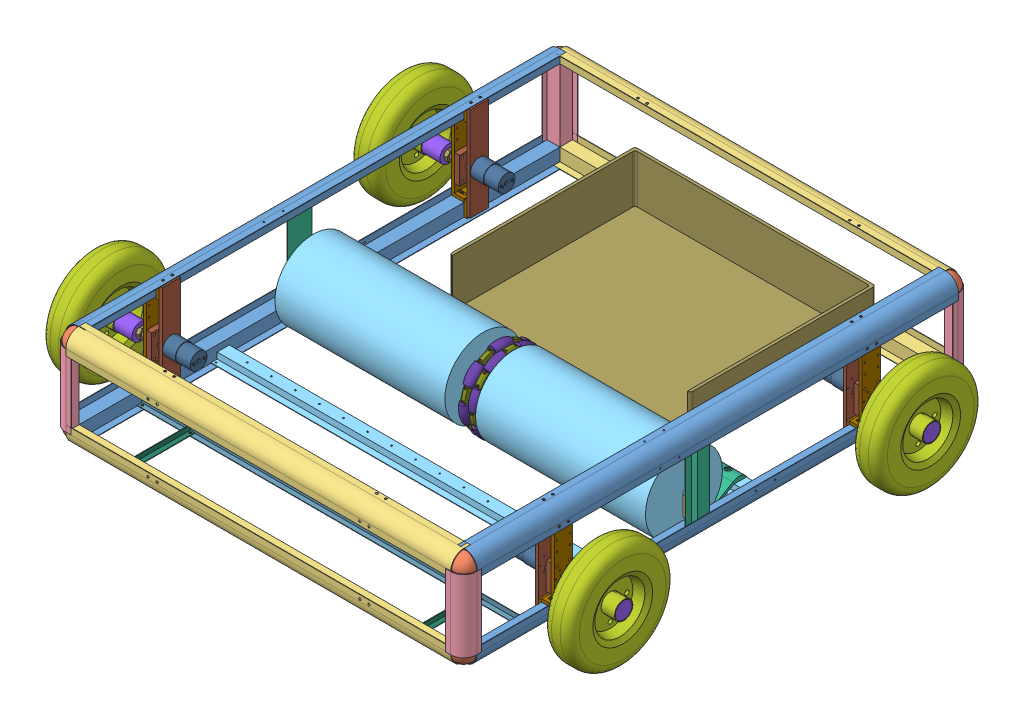
SolidWorks assembly Chasis Completo, configuration Predeterminado. Lengths in mm.
Overall size (1103.46 320.76 1054.8).
153 component instances, 30 part files, 76 mates.
Components (placement in the parent):
- Chasis Con Pala-1: Chasis Con Pala [Predeterminado] at (1005.1778 -86.1734 2178.1908) x (0 0 1) z (-1 0 0) size (1054.8 242.15 854.8)
  - ChasisConBasesMotor-1: ChasisConBasesMotor [Predeterminado] at (-1083.3487 23.6381 -1054.8) size (1054.8 204.8 854.8)
    - Chasis-1: Chasis [Predeterminado] at (1241.3285 35.949 1054.8) size (1054.8 204.8 854.8)
      - MarcoBaseParales-1: MarcoBaseParales [Predeterminado] at (-1311.4332 104.5123 1) size (1054.8 177.4 854.8)
        - MarcoBase-1: MarcoBase [Predeterminado] at (-969.9374 -232.4227 646.0297) x (0 1 0) z (1 0 0) size (77.4 854.8 1053.8)
          - Angulo-1: Angulo [Predeterminado] at (-20.7639 -5.9297 1000) x (-1 0 0) z (0 0 1) size (40.4 40.4 1000)
          - Angulo 90 perfil-1: Angulo 90 perfil [Predeterminado] at (-7.0639 7.7703 1500) x (-1 0 0) z (0 0 -1) size (75.4 75.4 75.4)
          - Angulo 90 perfil-2: Angulo 90 perfil [Predeterminado] at (-7.0639 7.7703 500) x (0 0 -1) z (1 0 0) size (75.4 75.4 75.4)
          - AnguloFrontal-1: AnguloFrontal [Predeterminado] at (-20.7639 407.7703 486.3) x (-1 0 0) z (0 -1 0) size (40.4 40.4 800)
          - AnguloFrontal-2: AnguloFrontal [Predeterminado] at (-20.7639 407.7703 1512.7) x (-1 0 0) z (0 1 0) size (40.4 40.4 800)
          - Angulo-2: Angulo [Predeterminado] at (-20.7639 821.4703 999) x (0 1 0) z (0 0 1) size (40.4 40.4 1000)
          - Angulo 90 perfil-3: Angulo 90 perfil [Predeterminado] at (-7.0639 807.7703 1499) x (0 1 0) z (0 0 -1) size (75.4 75.4 75.4)
          - Angulo 90 perfil-5: Angulo 90 perfil [Predeterminado] at (-7.0639 807.7703 500) x (0 0 -1) z (0 -1 0) size (75.4 75.4 75.4)
        - AnguloParal-1: AnguloParal [Predeterminado] at (-483.6374 -164.4866 1467.5) x (-1 0 0) z (0 1 0) size (37.4 37.4 150)
        - AnguloParal-2: AnguloParal [Predeterminado] at (542.7626 -164.4866 1467.5) x (1 0 0) z (0 -1 0) size (37.4 37.4 150)
        - AnguloParal-3: AnguloParal [Predeterminado] at (543.7626 -164.4866 640.1) x (1 0 0) z (0 1 0) size (37.4 37.4 150)
        - AnguloParal-4: AnguloParal [Predeterminado] at (-483.6374 -164.4866 640.2072) x (-1 0 0) z (0 -1 0) size (37.4 37.4 150)
      - MarcoBase-1: MarcoBase [Predeterminado] at (-282.3706 7.9618 647.0297) x (0 -1 0) z (-1 0 0) size (77.4 854.8 1053.8)
        - Angulo-1: Angulo [Predeterminado] at (-20.7639 -5.9297 1000) x (-1 0 0) z (0 0 1) size (40.4 40.4 1000)
        - Angulo 90 perfil-1: Angulo 90 perfil [Predeterminado] at (-7.0639 7.7703 1500) x (-1 0 0) z (0 0 -1) size (75.4 75.4 75.4)
        - Angulo 90 perfil-2: Angulo 90 perfil [Predeterminado] at (-7.0639 7.7703 500) x (0 0 -1) z (1 0 0) size (75.4 75.4 75.4)
        - AnguloFrontal-1: AnguloFrontal [Predeterminado] at (-20.7639 407.7703 486.3) x (-1 0 0) z (0 -1 0) size (40.4 40.4 800)
        - AnguloFrontal-2: AnguloFrontal [Predeterminado] at (-20.7639 407.7703 1512.7) x (-1 0 0) z (0 1 0) size (40.4 40.4 800)
        - Angulo-2: Angulo [Predeterminado] at (-20.7639 821.4703 999) x (0 1 0) z (0 0 1) size (40.4 40.4 1000)
        - Angulo 90 perfil-3: Angulo 90 perfil [Predeterminado] at (-7.0639 807.7703 1499) x (0 1 0) z (0 0 -1) size (75.4 75.4 75.4)
        - Angulo 90 perfil-5: Angulo 90 perfil [Predeterminado] at (-7.0639 807.7703 500) x (0 0 -1) z (0 -1 0) size (75.4 75.4 75.4)
    - Perfil Cuadrado-1: Perfil Cuadrado [Predeterminado] at (-140.5421 -125.4063 2109.5744) x (0.999999 0 0.001266) z (-0.001266 0 0.999999) size (50.8 13.7 800)
  - Pala Final con cinta-1: Pala Final con cinta [Predeterminado] at (-1316.8259 -114.6069 1804.6573) x (-0.999999 0 -0.001266) z (0.001266 0 -0.999999) size (135.72 60.94 750)
    - Pala Final-1: Pala Final [Predeterminado] at (-89.6383 2.5012 300) size (135.72 55.88 750)
      - SoportePala-1: SoportePala [Predeterminado] at (-102.2251 6.5255 0) size (135.72 55.88 150)
        - pala2-1: pala2 [Predeterminado] at (85.8775 17.5121 150) size (98.62 43.88 150)
        - protecto pala-1: protecto pala [Predeterminado] at (39.6775 -17.4879 150) size (110.9 15 150)
      - SoportePala-2: SoportePala [Predeterminado] at (-102.2251 6.5255 150) size (135.72 55.88 150)
        - pala2-1: pala2 [Predeterminado] at (85.8775 17.5121 150) size (98.62 43.88 150)
        - protecto pala-1: protecto pala [Predeterminado] at (39.6775 -17.4879 150) size (110.9 15 150)
      - SoportePala-3: SoportePala [Predeterminado] at (-102.2251 6.5255 300) size (135.72 55.88 150)
        - pala2-1: pala2 [Predeterminado] at (85.8775 17.5121 150) size (98.62 43.88 150)
        - protecto pala-1: protecto pala [Predeterminado] at (39.6775 -17.4879 150) size (110.9 15 150)
      - SoportePala-4: SoportePala [Predeterminado] at (-102.2251 6.5255 450) size (135.72 55.88 150)
        - pala2-1: pala2 [Predeterminado] at (85.8775 17.5121 150) size (98.62 43.88 150)
        - protecto pala-1: protecto pala [Predeterminado] at (39.6775 -17.4879 150) size (110.9 15 150)
      - SoportePala-5: SoportePala [Predeterminado] at (-102.2251 6.5255 600) size (135.72 55.88 150)
        - pala2-1: pala2 [Predeterminado] at (85.8775 17.5121 150) size (98.62 43.88 150)
        - protecto pala-1: protecto pala [Predeterminado] at (39.6775 -17.4879 150) size (110.9 15 150)
    - cinta flexy Recogedor-1: cinta flexy Recogedor [Predeterminado] at (-170.4213 -15.5255 750) x (0 0 1) z (-0.5 0.866025 0) size (750 40 4)
- Soporte Principal Del Chasis-1: Soporte Principal Del Chasis [Predeterminado] at (328.5899 -87.131 1174.7549) x (0 0 -1) z (1 0 0) size (71.11 203.98 109.8)
  - soporte Llantas-1: soporte Llantas [Predeterminado] at (-199.0451 0.5704 44.994) size (71.11 203.98 26.69)
  - instrument ball bearing_ai-1: instrument ball bearing_ai [Rodamiento Rodillo Llanta] at (-199.0451 -22.4296 36.994) x (0 0 -1) z (1 0 0) size (6.35 28.57 28.57)
  - SOPORTE BALINERA-1: SOPORTE BALINERA [Predeterminado] at (-199.0451 -22.4296 33.819) size (38 56 10.5)
  - hex jam nut_ai-1: hex jam nut_ai [HJNUT 0.5000-13-D-S] at (-199.0451 -22.4296 73.5162) x (0.739057 0.673642 0) z (0 0 1) size (19.05 22 8.2)
  - heavy hex finished bolt_ai-1: heavy hex finished bolt_ai [Tornilleria LLantas] at (-199.0451 -22.4296 -3.681) x (0 0 1) z (0.319798 -0.947486 0) size (109.8 25.66 22.23)
- Soporte Principal Del Chasis-2: Soporte Principal Del Chasis [Predeterminado] at (328.5899 -87.131 534.7549) x (0 0 -1) z (1 0 0) size (71.11 203.98 109.8)
  - soporte Llantas-1: soporte Llantas [Predeterminado] at (-199.0451 0.5704 44.994) size (71.11 203.98 26.69)
  - instrument ball bearing_ai-1: instrument ball bearing_ai [Rodamiento Rodillo Llanta] at (-199.0451 -22.4296 36.994) x (0 0 -1) z (1 0 0) size (6.35 28.57 28.57)
  - SOPORTE BALINERA-1: SOPORTE BALINERA [Predeterminado] at (-199.0451 -22.4296 33.819) size (38 56 10.5)
  - hex jam nut_ai-1: hex jam nut_ai [HJNUT 0.5000-13-D-S] at (-199.0451 -22.4296 73.5162) x (0.739057 0.673642 0) z (0 0 1) size (19.05 22 8.2)
  - heavy hex finished bolt_ai-1: heavy hex finished bolt_ai [Tornilleria LLantas] at (-199.0451 -22.4296 -3.681) x (0 0 1) z (0.319798 -0.947486 0) size (109.8 25.66 22.23)
- Soporte Principal Del Chasis-3: Soporte Principal Del Chasis [Predeterminado] at (-427.8342 -87.131 933.8451) x (0 0 1) z (-1 0 0) size (71.11 203.98 109.8)
  - soporte Llantas-1: soporte Llantas [Predeterminado] at (-199.0451 0.5704 44.994) size (71.11 203.98 26.69)
  - instrument ball bearing_ai-1: instrument ball bearing_ai [Rodamiento Rodillo Llanta] at (-199.0451 -22.4296 36.994) x (0 0 -1) z (1 0 0) size (6.35 28.57 28.57)
  - SOPORTE BALINERA-1: SOPORTE BALINERA [Predeterminado] at (-199.0451 -22.4296 33.819) size (38 56 10.5)
  - hex jam nut_ai-1: hex jam nut_ai [HJNUT 0.5000-13-D-S] at (-199.0451 -22.4296 73.5162) x (0.739057 0.673642 0) z (0 0 1) size (19.05 22 8.2)
  - heavy hex finished bolt_ai-1: heavy hex finished bolt_ai [Tornilleria LLantas] at (-199.0451 -22.4296 -3.681) x (0 0 1) z (0.319798 -0.947486 0) size (109.8 25.66 22.23)
- Soporte Principal Del Chasis-4: Soporte Principal Del Chasis [Predeterminado] at (-427.8342 -87.131 1573.8451) x (0 0 1) z (-1 0 0) size (71.11 203.98 109.8)
  - soporte Llantas-1: soporte Llantas [Predeterminado] at (-199.0451 0.5704 44.994) size (71.11 203.98 26.69)
  - instrument ball bearing_ai-1: instrument ball bearing_ai [Rodamiento Rodillo Llanta] at (-199.0451 -22.4296 36.994) x (0 0 -1) z (1 0 0) size (6.35 28.57 28.57)
  - SOPORTE BALINERA-1: SOPORTE BALINERA [Predeterminado] at (-199.0451 -22.4296 33.819) size (38 56 10.5)
  - hex jam nut_ai-1: hex jam nut_ai [HJNUT 0.5000-13-D-S] at (-199.0451 -22.4296 73.5162) x (0.739057 0.673642 0) z (0 0 1) size (19.05 22 8.2)
  - heavy hex finished bolt_ai-1: heavy hex finished bolt_ai [Tornilleria LLantas] at (-199.0451 -22.4296 -3.681) x (0 0 1) z (0.319798 -0.947486 0) size (109.8 25.66 22.23)
- soporte en T-1: soporte en T [Predeterminado] at (-49.6222 -186.9416 1423.3) x (0 0 -1) z (1 0 0) size (20 10.5 800)
- soporte en T pequeño-1: soporte en T pequeño [Predeterminado] at (249.8778 -185.9416 1488.8) size (20 10.5 130)
- soporte en T pequeño-2: soporte en T pequeño [Predeterminado] at (-349.1222 -185.9416 1488.8) size (20 10.5 130)
- Cepillo Completo-2: Cepillo Completo [Predeterminado] at (4.6536 191.4969 992.2498) x (-1 0 0) z (0 -0.963977 0.265985) size (825.32 260.79 260.79)
  - Rueda Doble Emsablada-1: Rueda Doble Emsablada [Predeterminado] at (213.8906 -0.5706 307.9688) x (0 0 1) z (-1 0 0) size (171.23 167.9 69.84)
    - LLanta OmniDir-1: LLanta OmniDir [Default] at (0.1906 -38.8804 113.5972) size (171.23 167.9 52.77)
      - OmniRueda-1: OmniRueda [Default] at (1.0225 6.9291 -0.7395) size (171.23 164.9 32.77)
        - base1-1: base1 [Default] at (21.7624 30.7176 48.3759) size (155.19 151.79 15.2)
        - tambor-1: tambor [Default] at (21.7309 100.0125 48.3759) size (38.41 23.31 23.31)
        - tambor-2: tambor [Default] at (75.8785 73.9985 48.3759) x (0.62349 -0.781831 0) z (0.006132 0.00489 0.999969) size (38.41 23.31 23.31)
        - tambor-3: tambor [Default] at (-32.3241 74.0356 48.3759) x (0.62349 0.781831 0) z (-0.451651 0.36018 0.816261) size (38.41 23.31 23.31)
        - tambor-4: tambor [Default] at (89.32 15.2982 48.3759) x (0.222521 0.974928 0) z (-0.021105 0.004817 0.999766) size (38.41 23.31 23.31)
        - tambor-5: tambor [Default] at (-45.7853 15.2549 48.3759) x (0.222521 -0.974928 0) z (-0.760422 -0.173561 0.625808) size (38.41 23.31 23.31)
        - tambor-6: tambor [Default] at (51.6132 -31.8186 48.3759) x (0.900969 0.433884 0) z (-0.125061 0.259692 0.957559) size (38.41 23.31 23.31)
        - tambor-7: tambor [Default] at (-8.5258 -31.6079 48.3759) x (0.900969 -0.433884 0) z (0.089476 0.185799 0.978505) size (38.41 23.31 23.31)
        - Part1-1: Part1 [Default] at (46.9251 100.0125 48.3759) x (0 -0.961459 -0.274948) z (-1 0 0) size (5.83 5.83 50.33)
        - Part1-2: Part1 [Default] at (-16.7258 93.5952 48.3759) x (0.669349 -0.533788 -0.516762) z (-0.62349 -0.781831 0) size (5.83 5.83 50.33)
        - Part1-3: Part1 [Default] at (91.628 54.2493 48.3759) x (-0.207776 -0.165696 0.964041) z (-0.62349 0.781831 0) size (5.83 5.83 50.33)
        - Part1-4: Part1 [Default] at (94.9204 39.8354 48.3759) x (-0.649686 0.148286 0.7456) z (-0.222521 -0.974928 0) size (5.83 5.83 50.33)
        - Part1-5: Part1 [Default] at (14.3725 -42.6351 48.3759) x (0.3295 0.684213 0.650602) z (-0.900969 0.433884 0) size (5.83 5.83 50.33)
        - Part1-6: Part1 [Default] at (74.5043 -20.7948 48.3759) x (-0.412763 0.857111 0.308201) z (-0.900969 -0.433884 0) size (5.83 5.83 50.33)
        - Part1-7: Part1 [Default] at (-40.1946 -9.2394 48.3759) x (0.950484 0.216942 0.222521) z (-0.222521 0.974928 0) size (5.83 5.83 50.33)
      - OmniRueda-2: OmniRueda [Default] at (1.0225 68.3643 116.0123) x (1 0 0) z (0 0 -1) size (171.23 164.9 32.77)
        - base1-1: base1 [Default] at (21.7624 30.7176 48.3759) size (155.19 151.79 15.2)
        - tambor-1: tambor [Default] at (21.7309 100.0125 48.3759) size (38.41 23.31 23.31)
        - tambor-2: tambor [Default] at (75.8785 73.9985 48.3759) x (0.62349 -0.781831 0) z (0.006132 0.00489 0.999969) size (38.41 23.31 23.31)
        - tambor-3: tambor [Default] at (-32.3241 74.0356 48.3759) x (0.62349 0.781831 0) z (-0.451651 0.36018 0.816261) size (38.41 23.31 23.31)
        - tambor-4: tambor [Default] at (89.32 15.2982 48.3759) x (0.222521 0.974928 0) z (-0.021105 0.004817 0.999766) size (38.41 23.31 23.31)
        - tambor-5: tambor [Default] at (-45.7853 15.2549 48.3759) x (0.222521 -0.974928 0) z (-0.760422 -0.173561 0.625808) size (38.41 23.31 23.31)
        - tambor-6: tambor [Default] at (51.6132 -31.8186 48.3759) x (0.900969 0.433884 0) z (-0.125061 0.259692 0.957559) size (38.41 23.31 23.31)
        - tambor-7: tambor [Default] at (-8.5258 -31.6079 48.3759) x (0.900969 -0.433884 0) z (0.089476 0.185799 0.978505) size (38.41 23.31 23.31)
        - Part1-1: Part1 [Default] at (46.9251 100.0125 48.3759) x (0 -0.961459 -0.274948) z (-1 0 0) size (5.83 5.83 50.33)
        - Part1-2: Part1 [Default] at (-16.7258 93.5952 48.3759) x (0.669349 -0.533788 -0.516762) z (-0.62349 -0.781831 0) size (5.83 5.83 50.33)
        - Part1-3: Part1 [Default] at (91.628 54.2493 48.3759) x (-0.207776 -0.165696 0.964041) z (-0.62349 0.781831 0) size (5.83 5.83 50.33)
        - Part1-4: Part1 [Default] at (94.9204 39.8354 48.3759) x (-0.649686 0.148286 0.7456) z (-0.222521 -0.974928 0) size (5.83 5.83 50.33)
        - Part1-5: Part1 [Default] at (14.3725 -42.6351 48.3759) x (0.3295 0.684213 0.650602) z (-0.900969 0.433884 0) size (5.83 5.83 50.33)
        - Part1-6: Part1 [Default] at (74.5043 -20.7948 48.3759) x (-0.412763 0.857111 0.308201) z (-0.900969 -0.433884 0) size (5.83 5.83 50.33)
        - Part1-7: Part1 [Default] at (-40.1946 -9.2394 48.3759) x (0.950484 0.216942 0.222521) z (-0.222521 0.974928 0) size (5.83 5.83 50.33)
    - AdaptadorM2R-1: AdaptadorM2R [Default] at (22.9755 -1.2337 176.1929) size (74.17 77.45 15.3)
    - AdaptadorM3R-1: AdaptadorM3R [Default] at (22.9755 -1.2337 164.0753) x (-1 0 0) z (0 0 -1) size (74.17 77.45 36.3)
  - Cepillo Medio Ensamble-1: Cepillo Medio Ensamble [Predeterminado] at (431.5469 -55.7311 346.0419) x (1 0 0) z (0 0.963977 -0.265985) size (403.4 212.03 212.03)
    - Soporte Lateral Rodillo-1: Soporte Lateral Rodillo [Predeterminado] at (32.8715 0.2099 56) x (0 0 -1) z (-1 0 0) size (50 40 17)
    - Anillos Rodillo2-1: Anillos Rodillo2 [Predeterminado] at (17.3715 0.2099 56) x (0 0 -1) z (1 0 0) size (9.5 9.5 13)
    - Cepillo-1: Cepillo [Predeterminado] at (-168.8285 0.2099 56) x (0 -0.415694 -0.909505) z (0 0.909505 -0.415694) size (160 398.4 160)
  - Cepillo Medio Ensamble-2: Cepillo Medio Ensamble [Predeterminado] at (-323.0338 -55.8428 345.6371) x (-1 0 0) z (0 0.963977 -0.265985) size (403.4 212.03 212.03)
    - Soporte Lateral Rodillo-1: Soporte Lateral Rodillo [Predeterminado] at (32.8715 0.2099 56) x (0 0 -1) z (-1 0 0) size (50 40 17)
    - Anillos Rodillo2-1: Anillos Rodillo2 [Predeterminado] at (17.3715 0.2099 56) x (0 0 -1) z (1 0 0) size (9.5 9.5 13)
    - Cepillo-1: Cepillo [Predeterminado] at (-168.8285 0.2099 56) x (0 -0.415694 -0.909505) z (0 0.909505 -0.415694) size (160 398.4 160)
- Perfil Cuadrado 15cm-1: Perfil Cuadrado 15cm [Predeterminado] at (363.0589 -86.5606 1082.4154) x (0 0 -1) z (0 -1 0) size (50.8 13.7 150)
- Perfil Cuadrado 15cm-2: Perfil Cuadrado 15cm [Predeterminado] at (-462.3032 -86.5606 1082.4154) x (0 0 -1) z (0 1 0) size (50.8 13.7 150)
- Llanta Fija-1: Llanta Fija [Predeterminado] at (251.1061 -97.6049 1378.7964) x (0 0 1) z (1 0 0) size (220 220 100)
  - Llanta-1: Llanta [Predeterminado] at (-4.9964 11.9557 220) x (1 0 0) z (0 -1 0) size (220 62 220)
  - Sujetadores Llantas-1: Sujetadores Llantas [Predeterminado] at (-4.9964 11.9557 151) size (35 35 100)
- Llanta Fija-2: Llanta Fija [Predeterminado] at (251.1061 -97.6049 738.7964) x (0 0 1) z (1 0 0) size (220 220 100)
  - Llanta-1: Llanta [Predeterminado] at (-4.9964 11.9557 220) x (1 0 0) z (0 -1 0) size (220 62 220)
  - Sujetadores Llantas-1: Sujetadores Llantas [Predeterminado] at (-4.9964 11.9557 151) size (35 35 100)
- Llanta Fija-3: Llanta Fija [Predeterminado] at (-350.3504 -120.7316 1381.366) x (0 0.135116 0.99083) z (-1 0 0) size (220 220 100)
  - Llanta-1: Llanta [Predeterminado] at (-4.9964 11.9557 220) x (1 0 0) z (0 -1 0) size (220 62 220)
  - Sujetadores Llantas-1: Sujetadores Llantas [Predeterminado] at (-4.9964 11.9557 151) size (35 35 100)
- Llanta Fija-4: Llanta Fija [Predeterminado] at (-350.3504 -121.5163 739.7964) x (0 0 1) z (-1 0 0) size (220 220 100)
  - Llanta-1: Llanta [Predeterminado] at (-4.9964 11.9557 220) x (1 0 0) z (0 -1 0) size (220 62 220)
  - Sujetadores Llantas-1: Sujetadores Llantas [Predeterminado] at (-4.9964 11.9557 151) size (35 35 100)
- Suplemento Transmision-1: Suplemento Transmision [Predeterminado] at (344.0278 -172.9416 1373.8) x (0 0 1) z (1 0 0) size (38 30 6.35)
- Suplemento Transmision-2: Suplemento Transmision [Predeterminado] at (350.3778 -0.1795 1373.8) x (0 0 -1) z (-1 0 0) size (38 30 6.35)
- Suplemento Transmision-3: Suplemento Transmision [Predeterminado] at (344.0278 -172.9416 733.8) x (0 0 1) z (1 0 0) size (38 30 6.35)
- Suplemento Transmision-4: Suplemento Transmision [Predeterminado] at (344.0278 -0.1795 733.8) x (0 0 -1) z (1 0 0) size (38 30 6.35)
- Suplemento Transmision-5: Suplemento Transmision [Predeterminado] at (-449.6222 -172.9416 734.8) x (0 0 -1) z (1 0 0) size (38 30 6.35)
- Suplemento Transmision-6: Suplemento Transmision [Predeterminado] at (-449.6222 -0.1795 734.8) x (0 0 -1) z (1 0 0) size (38 30 6.35)
- Suplemento Transmision-7: Suplemento Transmision [Predeterminado] at (-449.6222 -0.1795 1374.8) x (0 0 -1) z (1 0 0) size (38 30 6.35)
- Suplemento Transmision-8: Suplemento Transmision [Predeterminado] at (-449.6222 -172.9416 1374.8) x (0 0 -1) z (1 0 0) size (38 30 6.35)
- Motor Montado-1: Motor Montado [Predeterminado] at (231.4278 -104.5532 1373.4137) x (0 0 -1) z (1 0 0) size (38 195 89.5)
  - Motores Pololu-1: Motores Pololu [Predeterminado] at (-0.3863 2.7426 79.75) size (36.8 36.8 89.5)
  - soporte motor-1: soporte motor [Predeterminado] at (-0.3863 25.7426 109.425) size (38 195 6.35)
- Motor Montado-2: Motor Montado [Predeterminado] at (231.4278 -104.5532 733.4137) x (0 0 -1) z (1 0 0) size (38 195 89.5)
  - Motores Pololu-1: Motores Pololu [Predeterminado] at (-0.3863 2.7426 79.75) size (36.8 36.8 89.5)
  - soporte motor-1: soporte motor [Predeterminado] at (-0.3863 25.7426 109.425) size (38 195 6.35)
- Motor Montado-3: Motor Montado [Predeterminado] at (-330.6722 -104.5532 1375.1863) x (0 0 1) z (-1 0 0) size (38 195 89.5)
  - Motores Pololu-1: Motores Pololu [Predeterminado] at (-0.3863 2.7426 79.75) size (36.8 36.8 89.5)
  - soporte motor-1: soporte motor [Predeterminado] at (-0.3863 25.7426 109.425) size (38 195 6.35)
- Motor Montado-4: Motor Montado [Predeterminado] at (-330.6722 -104.5532 735.1863) x (0 0 1) z (-1 0 0) size (38 195 89.5)
  - Motores Pololu-1: Motores Pololu [Predeterminado] at (-0.3863 2.7426 79.75) size (36.8 36.8 89.5)
  - soporte motor-1: soporte motor [Predeterminado] at (-0.3863 25.7426 109.425) size (38 195 6.35)
- Canastilla-1: Canastilla [Predeterminado] at (-43.3214 -187.9416 747.3) x (-1 0 0) z (0 0 -1) size (500 105 385)
- Perfil Cuadrado-1: Perfil Cuadrado [Predeterminado] at (-49.6222 -187.9416 1254.442) x (0 0 -1) z (1 0 0) size (50.8 13.7 800)
Mates (geometry in assembly coordinates):
- Concéntrica1: concentric aligned: cylinder of Chasis Con Pala-1/ChasisConBasesMotor-1/Chasis-1/MarcoBase-1/Angulo-1 through (367.7589 -16.5606 1364.3) axis (1 0 0) radius 2.3813; cylinder of Soporte Principal Del Chasis-1/soporte Llantas-1 through (351.3589 -16.5606 1364.3) axis (1 0 0) radius 1.9844
- Concéntrica2: concentric aligned: circle of Chasis Con Pala-1/ChasisConBasesMotor-1/Chasis-1/MarcoBase-1/Angulo-1; cylinder of Soporte Principal Del Chasis-1/soporte Llantas-1 through (351.3589 -16.5606 1383.3) axis (1 0 0) radius 1.9844
- Coincidente1: coincident anti-aligned: plane of Chasis Con Pala-1/ChasisConBasesMotor-1/Chasis-1/MarcoBaseParales-1/MarcoBase-1/Angulo-1 through (376.7589 -175.2606 1554.8) normal (-1 0 0); plane of Soporte Principal Del Chasis-1/soporte Llantas-1 through (376.7589 -86.5606 1373.8) normal (1 0 0)
- Concéntrica3: concentric aligned: cylinder of Chasis Con Pala-1/ChasisConBasesMotor-1/Chasis-1/MarcoBase-1/Angulo-1 through (367.7589 -16.5606 743.3) axis (1 0 0) radius 2.3813; cylinder of Soporte Principal Del Chasis-2/soporte Llantas-1 through (351.3589 -16.5606 743.3) axis (1 0 0) radius 1.9844
- Concéntrica4: concentric aligned: cylinder of Chasis Con Pala-1/ChasisConBasesMotor-1/Chasis-1/MarcoBase-1/Angulo-1 through (367.7589 -16.5606 724.3) axis (1 0 0) radius 2.3813; cylinder of Soporte Principal Del Chasis-2/soporte Llantas-1 through (351.3589 -16.5606 724.3) axis (1 0 0) radius 1.9844
- Coincidente2: coincident anti-aligned: plane of Chasis Con Pala-1/ChasisConBasesMotor-1/Chasis-1/MarcoBaseParales-1/MarcoBase-1/Angulo-1 through (376.7589 -175.2606 1554.8) normal (-1 0 0); plane of Soporte Principal Del Chasis-2/soporte Llantas-1 through (376.7589 -86.5606 733.8) normal (1 0 0)
- Concéntrica5: concentric aligned: cylinder of Chasis Con Pala-1/ChasisConBasesMotor-1/Chasis-1/MarcoBase-1/Angulo-2 through (-467.0032 -16.5606 744.3) axis (-1 0 0) radius 2.3813; cylinder of Soporte Principal Del Chasis-3/soporte Llantas-1 through (-450.6032 -16.5606 744.3) axis (-1 0 0) radius 1.9844
- Concéntrica6: concentric aligned: cylinder of Chasis Con Pala-1/ChasisConBasesMotor-1/Chasis-1/MarcoBase-1/Angulo-2 through (-467.0032 -16.5606 725.3) axis (-1 0 0) radius 2.3813; cylinder of Soporte Principal Del Chasis-3/soporte Llantas-1 through (-450.6032 -16.5606 725.3) axis (-1 0 0) radius 1.9844
- Coincidente3: coincident anti-aligned: plane of Chasis Con Pala-1/ChasisConBasesMotor-1/Chasis-1/MarcoBaseParales-1/MarcoBase-1/Angulo-2 through (-476.0032 -175.2606 1553.8) normal (1 0 0); plane of Soporte Principal Del Chasis-3/soporte Llantas-1 through (-476.0032 -86.5606 734.8) normal (-1 0 0)
- Concéntrica7: concentric aligned: cylinder of Chasis Con Pala-1/ChasisConBasesMotor-1/Chasis-1/MarcoBase-1/Angulo-2 through (-467.0032 -16.5606 1365.3) axis (-1 0 0) radius 2.3813; cylinder of Soporte Principal Del Chasis-4/soporte Llantas-1 through (-450.6032 -16.5606 1365.3) axis (-1 0 0) radius 1.9844
- Concéntrica8: concentric aligned: cylinder of Chasis Con Pala-1/ChasisConBasesMotor-1/Chasis-1/MarcoBase-1/Angulo-2 through (-467.0032 -16.5606 1384.3) axis (-1 0 0) radius 2.3813; cylinder of Soporte Principal Del Chasis-4/soporte Llantas-1 through (-450.6032 -16.5606 1384.3) axis (-1 0 0) radius 1.9844
- Coincidente4: coincident anti-aligned: plane of Chasis Con Pala-1/ChasisConBasesMotor-1/Chasis-1/MarcoBaseParales-1/MarcoBase-1/Angulo-2 through (-476.0032 -175.2606 1553.8) normal (1 0 0); plane of Soporte Principal Del Chasis-4/soporte Llantas-1 through (-476.0032 -86.5606 1374.8) normal (-1 0 0)
- Coincidente5: coincident anti-aligned: plane of Chasis Con Pala-1/ChasisConBasesMotor-1/Chasis-1/MarcoBaseParales-1/MarcoBase-1/Angulo-2 through (-463.3222 -187.9416 1553.8) normal (0 1 0); plane of soporte en T-1 through (350.3778 -187.9416 1433.3) normal (0 -1 0)
- Coincidente6: coincident anti-aligned: plane of Chasis Con Pala-1/ChasisConBasesMotor-1/Chasis-1/MarcoBaseParales-1/MarcoBase-1/Angulo-2 through (-449.6222 -175.2606 1553.8) normal (1 0 0); plane of soporte en T-1 through (-449.6222 -186.9416 1423.3) normal (-1 0 0)
- Coincidente7: coincident anti-aligned: plane of soporte en T-1 through (350.3778 -186.9416 1433.3) normal (0 1 0); plane of soporte en T pequeño-1 through (239.8778 -186.9416 1553.8) normal (0 -1 0)
- Coincidente8: coincident anti-aligned: plane of Chasis Con Pala-1/ChasisConBasesMotor-1/Chasis-1/MarcoBaseParales-1/MarcoBase-1/AnguloFrontal-2 through (-449.6222 -175.2606 1553.8) normal (0 0 -1); plane of soporte en T pequeño-1 through (249.8778 -185.9416 1553.8) normal (0 0 1)
- Coincidente9: coincident anti-aligned: plane of soporte en T-1 through (350.3778 -186.9416 1423.8) normal (0 0 1); plane of soporte en T pequeño-1 through (249.8778 -185.9416 1423.8) normal (0 0 -1)
- Distancia1: distance = 100 mm anti-aligned: plane of Chasis Con Pala-1/ChasisConBasesMotor-1/Chasis-1/MarcoBaseParales-1/MarcoBase-1/Angulo-1 through (350.3778 -175.2606 1554.8) normal (-1 0 0); plane of soporte en T pequeño-1 through (250.3778 -185.9416 1553.8) normal (1 0 0)
- Coincidente11: coincident anti-aligned: plane of soporte en T-1 through (350.3778 -186.9416 1423.8) normal (0 0 1); plane of soporte en T pequeño-2 through (-349.1222 -185.9416 1423.8) normal (0 0 -1)
- Distancia2: distance = 100 mm anti-aligned: plane of soporte en T pequeño-2 through (-349.6222 -185.9416 1553.8) normal (-1 0 0); plane of Chasis Con Pala-1/ChasisConBasesMotor-1/Chasis-1/MarcoBaseParales-1/MarcoBase-1/Angulo-2 through (-449.6222 -175.2606 1553.8) normal (1 0 0)
- Coincidente13: coincident anti-aligned: plane of soporte en T-1 through (350.3778 -186.9416 1433.3) normal (0 1 0); plane of soporte en T pequeño-2 through (-359.1222 -186.9416 1553.8) normal (0 -1 0)
- Coincidente14: coincident anti-aligned: plane of Chasis Con Pala-1/ChasisConBasesMotor-1/Chasis-1/MarcoBaseParales-1/MarcoBase-1/Angulo-1 through (376.7589 -175.2606 1554.8) normal (-1 0 0); plane of Perfil Cuadrado 15cm-1 through (376.7589 -161.5606 1082.4154) normal (1 0 0)
- Coincidente15: coincident anti-aligned: plane of Chasis Con Pala-1/ChasisConBasesMotor-1/Chasis-1/MarcoBaseParales-1/MarcoBase-1/Angulo-1 through (364.0778 -161.5606 1554.8) normal (0 1 0); plane of Perfil Cuadrado 15cm-1 through (363.0589 -161.5606 1082.4154) normal (0 -1 0)
- Coincidente18: coincident anti-aligned: plane of Cepillo Completo-2/Cepillo Medio Ensamble-2/Soporte Lateral Rodillo-1 through (363.0589 -127.046 1082.0154) normal (1 0 0); plane of Perfil Cuadrado 15cm-1 through (363.0589 -161.5606 1082.4154) normal (-1 0 0)
- Coincidente20: coincident aligned: plane of Cepillo Completo-2/Cepillo Medio Ensamble-2/Soporte Lateral Rodillo-1 through (358.0589 -147.046 1057.0154) normal (0 0 -1); plane of Perfil Cuadrado 15cm-1 through (363.0589 -161.5606 1057.0154) normal (0 0 -1)
- Coincidente22: coincident anti-aligned: plane of Chasis Con Pala-1/ChasisConBasesMotor-1/Chasis-1/MarcoBaseParales-1/MarcoBase-1/Angulo-2 through (-476.0032 -175.2606 1553.8) normal (1 0 0); plane of Perfil Cuadrado 15cm-2 through (-476.0032 -11.5606 1082.4154) normal (-1 0 0)
- Coincidente23: coincident anti-aligned: plane of Chasis Con Pala-1/ChasisConBasesMotor-1/Chasis-1/MarcoBaseParales-1/MarcoBase-1/Angulo-2 through (-463.3222 -161.5606 1553.8) normal (0 1 0); plane of Perfil Cuadrado 15cm-2 through (-462.3032 -161.5606 1082.4154) normal (0 -1 0)
- Coincidente24: coincident aligned: plane of Perfil Cuadrado 15cm-1 through (363.0589 -161.5606 1107.8154) normal (0 0 1); plane of Perfil Cuadrado 15cm-2 through (-462.3032 -11.5606 1107.8154) normal (0 0 1)
- Concéntrica9: concentric aligned: cylinder of Soporte Principal Del Chasis-1/heavy hex finished bolt_ai-1 through (324.9089 -109.5606 1373.8) axis (-1 0 0) radius 6.35; cylinder of Llanta Fija-1/Sujetadores Llantas-1 through (402.1061 -109.5606 1373.8) axis (-1 0 0) radius 5.3581
- Coincidente25: coincident anti-aligned: plane of Soporte Principal Del Chasis-1/hex jam nut_ai-1 through (402.1061 -122.3935 1387.879) normal (1 0 0); plane of Llanta Fija-1/Sujetadores Llantas-1 through (402.1061 -109.5606 1373.8) normal (-1 0 0)
- Concéntrica10: concentric aligned: cylinder of Soporte Principal Del Chasis-2/heavy hex finished bolt_ai-1 through (324.9089 -109.5606 733.8) axis (-1 0 0) radius 6.35; cylinder of Llanta Fija-2/Sujetadores Llantas-1 through (402.1061 -109.5606 733.8) axis (-1 0 0) radius 5.3581
- Coincidente26: coincident anti-aligned: plane of Soporte Principal Del Chasis-2/hex jam nut_ai-1 through (402.1061 -122.3935 747.879) normal (1 0 0); plane of Llanta Fija-2/Sujetadores Llantas-1 through (402.1061 -109.5606 733.8) normal (-1 0 0)
- Concéntrica11: concentric aligned: cylinder of Soporte Principal Del Chasis-4/heavy hex finished bolt_ai-1 through (-424.1532 -109.5606 1374.8) axis (1 0 0) radius 6.35; cylinder of Llanta Fija-3/Sujetadores Llantas-1 through (-501.3504 -109.5606 1374.8) axis (1 0 0) radius 5.3581
- Coincidente27: coincident anti-aligned: plane of Soporte Principal Del Chasis-4/hex jam nut_ai-1 through (-501.3504 -122.3935 1360.721) normal (-1 0 0); plane of Llanta Fija-3/Sujetadores Llantas-1 through (-501.3504 -109.5606 1374.8) normal (1 0 0)
- Concéntrica12: concentric aligned: cylinder of Soporte Principal Del Chasis-3/heavy hex finished bolt_ai-1 through (-424.1532 -109.5606 734.8) axis (1 0 0) radius 6.35; cylinder of Llanta Fija-4/Sujetadores Llantas-1 through (-501.3504 -109.5606 734.8) axis (1 0 0) radius 5.3581
- Coincidente28: coincident anti-aligned: plane of Soporte Principal Del Chasis-3/hex jam nut_ai-1 through (-501.3504 -122.3935 720.721) normal (-1 0 0); plane of Llanta Fija-4/Sujetadores Llantas-1 through (-501.3504 -109.5606 734.8) normal (1 0 0)
- Coincidente29: coincident anti-aligned: plane of Chasis Con Pala-1/ChasisConBasesMotor-1/Chasis-1/MarcoBaseParales-1/MarcoBase-1/Angulo-1 through (350.3778 -175.2606 1554.8) normal (-1 0 0); plane of Suplemento Transmision-1 through (350.3778 -172.9416 1373.8) normal (1 0 0)
- Coincidente30: coincident anti-aligned: plane of Chasis Con Pala-1/ChasisConBasesMotor-1/Chasis-1/MarcoBaseParales-1/MarcoBase-1/Angulo-1 through (364.0778 -187.9416 1554.8) normal (0 1 0); plane of Suplemento Transmision-1 through (350.3778 -187.9416 1354.8) normal (0 -1 0)
- Coincidente31: coincident aligned: plane of Soporte Principal Del Chasis-1/soporte Llantas-1 through (376.7589 -161.5606 1354.8) normal (0 0 -1); plane of Suplemento Transmision-1 through (350.3778 -157.9416 1354.8) normal (0 0 -1)
- Coincidente32: coincident anti-aligned: plane of Chasis Con Pala-1/ChasisConBasesMotor-1/Chasis-1/MarcoBase-1/Angulo-1 through (364.0778 14.8205 553.8) normal (0 -1 0); plane of Suplemento Transmision-2 through (344.0278 14.8205 1392.8) normal (0 1 0)
- Coincidente33: coincident anti-aligned: plane of Chasis Con Pala-1/ChasisConBasesMotor-1/Chasis-1/MarcoBase-1/Angulo-1 through (350.3778 2.1394 553.8) normal (-1 0 0); plane of Suplemento Transmision-2 through (350.3778 -0.1795 1373.8) normal (1 0 0)
- Coincidente34: coincident aligned: plane of Suplemento Transmision-1 through (350.3778 -157.9416 1354.8) normal (0 0 -1); plane of Suplemento Transmision-2 through (344.0278 14.8205 1354.8) normal (0 0 -1)
- Coincidente35: coincident anti-aligned: plane of Chasis Con Pala-1/ChasisConBasesMotor-1/Chasis-1/MarcoBaseParales-1/MarcoBase-1/Angulo-1 through (350.3778 -175.2606 1554.8) normal (-1 0 0); plane of Suplemento Transmision-3 through (350.3778 -172.9416 733.8) normal (1 0 0)
- Coincidente36: coincident anti-aligned: plane of Chasis Con Pala-1/ChasisConBasesMotor-1/Chasis-1/MarcoBaseParales-1/MarcoBase-1/Angulo-1 through (364.0778 -187.9416 1554.8) normal (0 1 0); plane of Suplemento Transmision-3 through (350.3778 -187.9416 714.8) normal (0 -1 0)
- Coincidente37: coincident aligned: plane of Soporte Principal Del Chasis-2/soporte Llantas-1 through (376.7589 -161.5606 752.8) normal (0 0 1); plane of Suplemento Transmision-3 through (350.3778 -157.9416 752.8) normal (0 0 1)
- Coincidente38: coincident anti-aligned: plane of Chasis Con Pala-1/ChasisConBasesMotor-1/Chasis-1/MarcoBase-1/Angulo-1 through (350.3778 2.1394 553.8) normal (-1 0 0); plane of Suplemento Transmision-4 through (350.3778 -0.1795 733.8) normal (1 0 0)
- Coincidente39: coincident anti-aligned: plane of Chasis Con Pala-1/ChasisConBasesMotor-1/Chasis-1/MarcoBase-1/Angulo-1 through (364.0778 14.8205 553.8) normal (0 -1 0); plane of Suplemento Transmision-4 through (350.3778 14.8205 752.8) normal (0 1 0)
- Coincidente40: coincident aligned: plane of Soporte Principal Del Chasis-2/soporte Llantas-1 through (376.7589 -161.5606 752.8) normal (0 0 1); plane of Suplemento Transmision-4 through (350.3778 -15.1795 752.8) normal (0 0 1)
- Coincidente41: coincident anti-aligned: plane of Chasis Con Pala-1/ChasisConBasesMotor-1/Chasis-1/MarcoBaseParales-1/MarcoBase-1/Angulo-2 through (-449.6222 -175.2606 1553.8) normal (1 0 0); plane of Suplemento Transmision-5 through (-449.6222 -172.9416 734.8) normal (-1 0 0)
- Coincidente42: coincident anti-aligned: plane of Chasis Con Pala-1/ChasisConBasesMotor-1/Chasis-1/MarcoBaseParales-1/MarcoBase-1/Angulo-2 through (-463.3222 -187.9416 1553.8) normal (0 1 0); plane of Suplemento Transmision-5 through (-443.2722 -187.9416 753.8) normal (0 -1 0)
- Coincidente43: coincident anti-aligned: plane of Chasis Con Pala-1/ChasisConBasesMotor-1/Chasis-1/MarcoBase-1/Angulo-2 through (-449.6222 2.1394 554.8) normal (1 0 0); plane of Suplemento Transmision-6 through (-449.6222 -0.1795 734.8) normal (-1 0 0)
- Coincidente44: coincident anti-aligned: plane of Chasis Con Pala-1/ChasisConBasesMotor-1/Chasis-1/MarcoBase-1/Angulo-2 through (-463.3222 14.8205 554.8) normal (0 -1 0); plane of Suplemento Transmision-6 through (-443.2722 14.8205 753.8) normal (0 1 0)
- Coincidente45: coincident aligned: plane of Soporte Principal Del Chasis-3/soporte Llantas-1 through (-476.0032 -161.5606 753.8) normal (0 0 1); plane of Suplemento Transmision-6 through (-443.2722 -15.1795 753.8) normal (0 0 1)
- Coincidente46: coincident aligned: plane of Soporte Principal Del Chasis-3/soporte Llantas-1 through (-476.0032 -161.5606 753.8) normal (0 0 1); plane of Suplemento Transmision-5 through (-443.2722 -187.9416 753.8) normal (0 0 1)
- Coincidente47: coincident anti-aligned: plane of Chasis Con Pala-1/ChasisConBasesMotor-1/Chasis-1/MarcoBaseParales-1/MarcoBase-1/Angulo-2 through (-449.6222 -175.2606 1553.8) normal (1 0 0); plane of Suplemento Transmision-7 through (-449.6222 -0.1795 1374.8) normal (-1 0 0)
- Coincidente48: coincident anti-aligned: plane of Chasis Con Pala-1/ChasisConBasesMotor-1/Chasis-1/MarcoBase-1/Angulo-2 through (-449.6222 2.1394 554.8) normal (1 0 0); plane of Suplemento Transmision-8 through (-449.6222 -172.9416 1374.8) normal (-1 0 0)
- Coincidente49: coincident anti-aligned: plane of Chasis Con Pala-1/ChasisConBasesMotor-1/Chasis-1/MarcoBase-1/Angulo-2 through (-463.3222 14.8205 554.8) normal (0 -1 0); plane of Suplemento Transmision-7 through (-443.2722 14.8205 1393.8) normal (0 1 0)
- Coincidente50: coincident anti-aligned: plane of Chasis Con Pala-1/ChasisConBasesMotor-1/Chasis-1/MarcoBaseParales-1/MarcoBase-1/Angulo-2 through (-463.3222 -187.9416 1553.8) normal (0 1 0); plane of Suplemento Transmision-8 through (-443.2722 -187.9416 1393.8) normal (0 -1 0)
- Coincidente51: coincident aligned: plane of Soporte Principal Del Chasis-4/soporte Llantas-1 through (-476.0032 -161.5606 1393.8) normal (0 0 1); plane of Suplemento Transmision-7 through (-443.2722 -15.1795 1393.8) normal (0 0 1)
- Coincidente52: coincident aligned: plane of Soporte Principal Del Chasis-4/soporte Llantas-1 through (-476.0032 -161.5606 1393.8) normal (0 0 1); plane of Suplemento Transmision-8 through (-443.2722 -187.9416 1393.8) normal (0 0 1)
- Concéntrica13: concentric aligned: cylinder of Soporte Principal Del Chasis-1/heavy hex finished bolt_ai-1 through (324.9089 -109.5606 1373.8) axis (-1 0 0) radius 6.35; cylinder of Motor Montado-1/Motores Pololu-1 through (365.6778 -109.5606 1373.8) axis (-1 0 0) radius 3
- Coincidente53: coincident anti-aligned: plane of Suplemento Transmision-2 through (344.0278 -0.1795 1373.8) normal (-1 0 0); plane of Motor Montado-1/soporte motor-1 through (344.0278 -78.8106 1373.8) normal (1 0 0)
- Coincidente54: coincident aligned: plane of Soporte Principal Del Chasis-1/soporte Llantas-1 through (376.7589 -161.5606 1354.8) normal (0 0 -1); plane of Motor Montado-1/soporte motor-1 through (344.0278 -153.8106 1354.8) normal (0 0 -1)
- Concéntrica14: concentric aligned: cylinder of Soporte Principal Del Chasis-2/heavy hex finished bolt_ai-1 through (324.9089 -109.5606 733.8) axis (-1 0 0) radius 6.35; cylinder of Motor Montado-2/Motores Pololu-1 through (365.6778 -109.5606 733.8) axis (-1 0 0) radius 3
- Coincidente55: coincident anti-aligned: plane of Suplemento Transmision-4 through (344.0278 -0.1795 733.8) normal (-1 0 0); plane of Motor Montado-2/soporte motor-1 through (344.0278 -78.8106 733.8) normal (1 0 0)
- Coincidente56: coincident aligned: plane of Soporte Principal Del Chasis-2/soporte Llantas-1 through (376.7589 -161.5606 714.8) normal (0 0 -1); plane of Motor Montado-2/soporte motor-1 through (344.0278 -153.8106 714.8) normal (0 0 -1)
- Concéntrica15: concentric aligned: cylinder of Soporte Principal Del Chasis-3/heavy hex finished bolt_ai-1 through (-424.1532 -109.5606 734.8) axis (1 0 0) radius 6.35; cylinder of Motor Montado-4/Motores Pololu-1 through (-464.9222 -109.5606 734.8) axis (1 0 0) radius 3
- Coincidente57: coincident anti-aligned: plane of Suplemento Transmision-5 through (-443.2722 -172.9416 734.8) normal (1 0 0); plane of Motor Montado-4/soporte motor-1 through (-443.2722 -78.8106 734.8) normal (-1 0 0)
- Coincidente58: coincident aligned: plane of Soporte Principal Del Chasis-3/soporte Llantas-1 through (-476.0032 -161.5606 715.8) normal (0 0 -1); plane of Motor Montado-4/soporte motor-1 through (-443.2722 -153.8106 715.8) normal (0 0 -1)
- Concéntrica16: concentric aligned: cylinder of Soporte Principal Del Chasis-4/heavy hex finished bolt_ai-1 through (-424.1532 -109.5606 1374.8) axis (1 0 0) radius 6.35; cylinder of Motor Montado-3/Motores Pololu-1 through (-464.9222 -109.5606 1374.8) axis (1 0 0) radius 3
- Coincidente59: coincident anti-aligned: plane of Suplemento Transmision-7 through (-443.2722 -0.1795 1374.8) normal (1 0 0); plane of Motor Montado-3/soporte motor-1 through (-443.2722 -78.8106 1374.8) normal (-1 0 0)
- Coincidente60: coincident aligned: plane of Soporte Principal Del Chasis-4/soporte Llantas-1 through (-476.0032 -161.5606 1355.8) normal (0 0 -1); plane of Motor Montado-3/soporte motor-1 through (-443.2722 -153.8106 1355.8) normal (0 0 -1)
- Coincidente61: coincident anti-aligned: plane of Chasis Con Pala-1/ChasisConBasesMotor-1/Chasis-1/MarcoBaseParales-1/MarcoBase-1/AnguloFrontal-1 through (350.3778 -175.2606 554.8) normal (0 0 1); plane of Canastilla-1 through (206.6786 -182.9416 554.8) normal (0 0 -1)
- Coincidente62: coincident anti-aligned: plane of Chasis Con Pala-1/ChasisConBasesMotor-1/Chasis-1/MarcoBaseParales-1/MarcoBase-1/AnguloFrontal-1 through (350.3778 -187.9416 541.1) normal (0 1 0); plane of Canastilla-1 through (-43.3214 -187.9416 747.3) normal (0 -1 0)
- Coincidente63: coincident anti-aligned: plane of Chasis Con Pala-1/ChasisConBasesMotor-1/Chasis-1/MarcoBaseParales-1/MarcoBase-1/Angulo-2 through (-463.3222 -187.9416 1553.8) normal (0 1 0); plane of Perfil Cuadrado-1 through (350.3778 -187.9416 1254.442) normal (0 -1 0)
- Coincidente64: coincident anti-aligned: plane of Chasis Con Pala-1/ChasisConBasesMotor-1/Chasis-1/MarcoBaseParales-1/MarcoBase-1/Angulo-1 through (350.3778 -175.2606 1554.8) normal (-1 0 0); plane of Perfil Cuadrado-1 through (350.3778 -187.9416 1254.442) normal (1 0 0)
